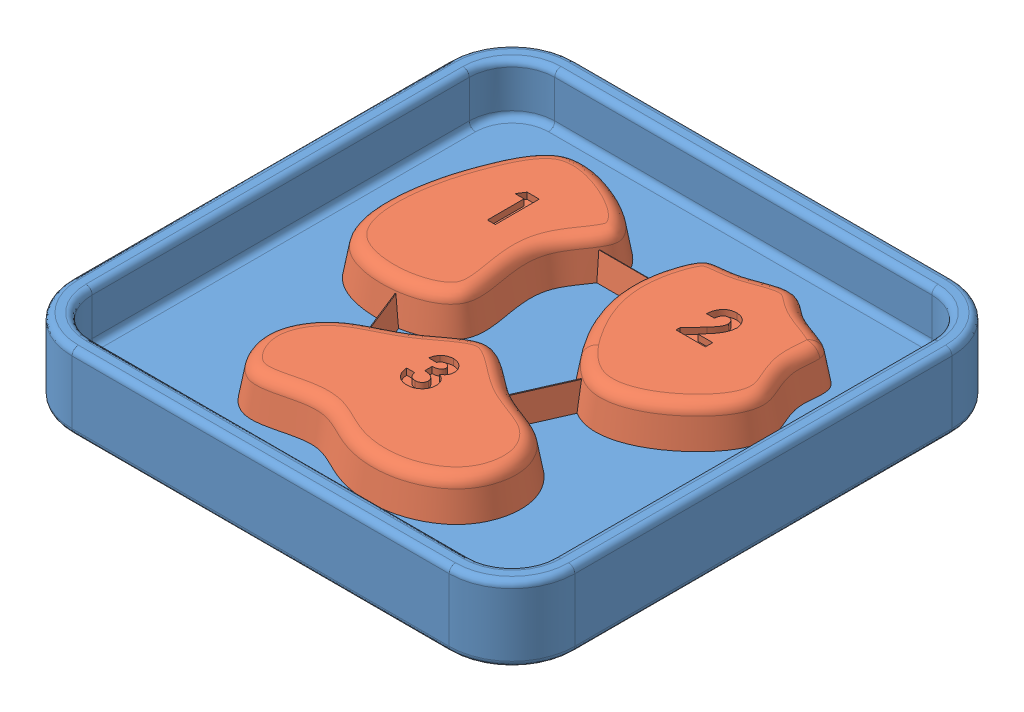
SolidWorks assembly Asteroid, configuration Default. Lengths in mm.
Overall size (40 6 40).
2 component instances, 2 part files, 2 mates.
Components (placement in the parent):
- Tile-1: Tile [Default] at (11.8682 15.8625 33.6863) size (40 6 40)
- Asteroid3-1: Asteroid3 [Default] at (11.8454 17.8625 33.2863) size (31.48 3.13 32.05)
Mates (geometry in assembly coordinates):
- Coincident1: coincident anti-aligned: plane of Tile-1 through (-3.1318 17.8625 48.6863) normal (0 1 0); plane of Asteroid3-1 through (7.9826 17.8625 30.8539) normal (0 -1 0)
- Coincident2: coincident anti-aligned: line of Tile-1 through (26.8682 17.8625 15.7863) axis (-1 0 0); line of Asteroid3-1 through (-5.6546 17.8625 15.7863) axis (1 0 0)
